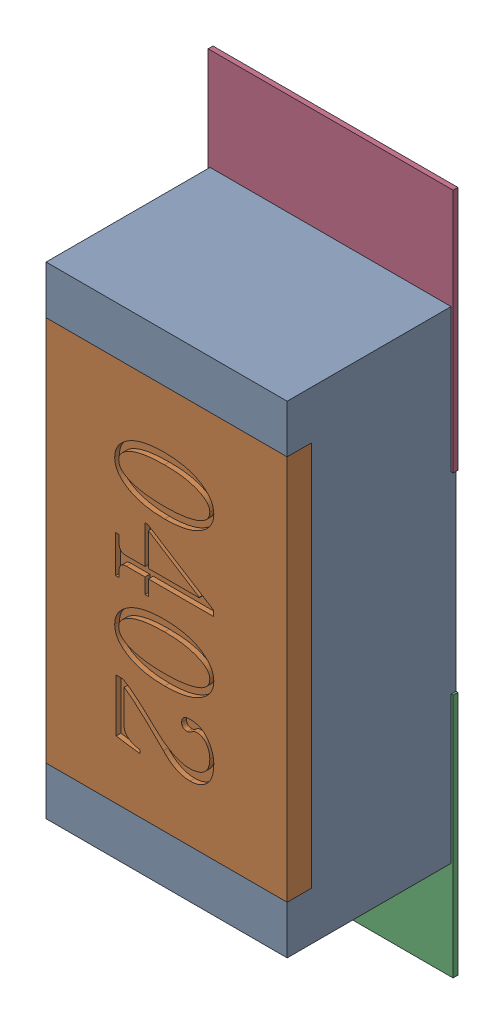
SolidWorks assembly R17, configuration Défaut. Lengths in mm.
Overall size (0.51 1.42 0.35).
5 component instances, 2 part files, 0 mates.
Components (placement in the parent):
- R0402-1: R0402 [Défaut] at (35.3313 -37.3254 0) x (0 -1 0) z (0 0 1) size (1 0.5 0.35)
- 6504207776-1: 6504207776 [Défaut] at (35.3314 -37.7754 0) size (0.51 0.51 0.01)
  - Extruded-1: Extruded [Défaut] at origin size (0.51 0.51 0.01)
- 6504207776-2: 6504207776 [Défaut] at (35.3314 -36.8683 0) size (0.51 0.51 0.01)
  - Extruded-1: Extruded [Défaut] at origin size (0.51 0.51 0.01)
